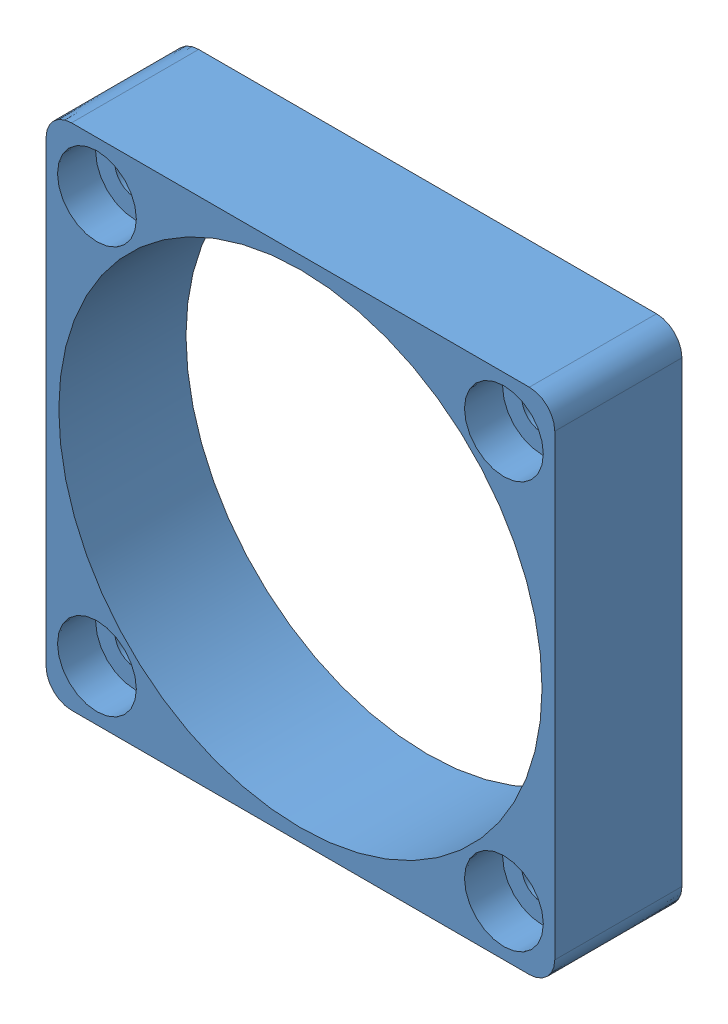
SolidWorks assembly MENDEL HOT END ACCESSORIES, configuration Default. Lengths in mm.
Overall size (40 40 10).
8 component instances, 6 part files, 0 mates.
Components (placement in the parent):
- 445-1: 445 [Default] at (-55.5693 -0.8563 29.9505)
- 847-1: 847 [Default] at (-166.4694 70.2579 38.3792)
- 847-2: 847 [Default] at (-214.5004 69.1131 64.0659)
- 953-1: 953 [Default] at (-179.4554 80.2628 85.9658) size (40 40 10)
- 433-1: 433 [Default] at (-39.8471 114.7066 47.7514)
- 433-2: 433 [Default] at (-285.5266 112.8871 176.3858)
- 430-1: 430 [Default] at (-77.3601 122.1173 62.1464)
- 167-1: 167 [Default] at (-70.4803 123.9073 57.3576)
